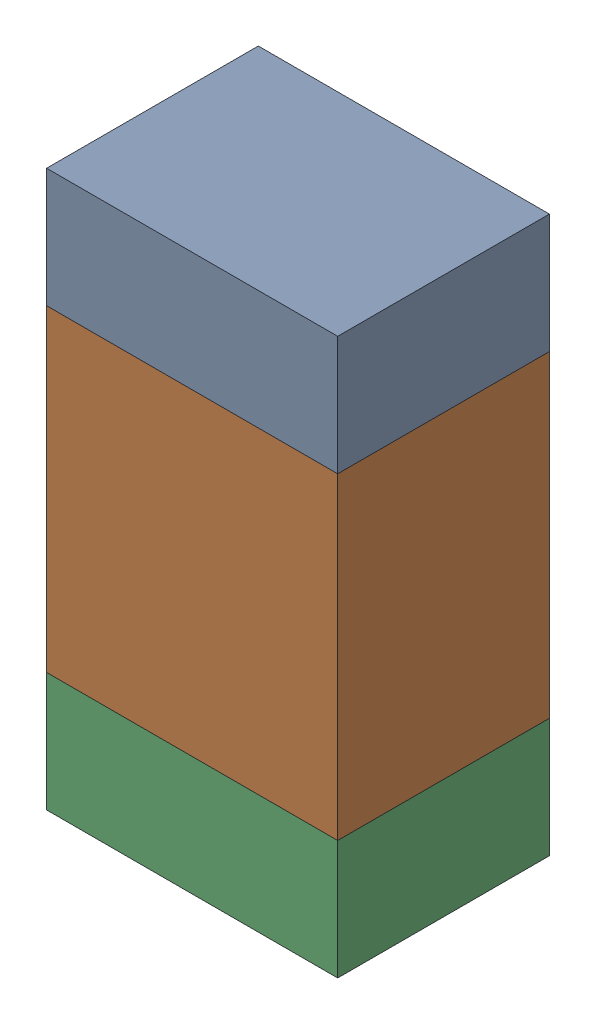
SolidWorks assembly R600_3PCB, configuration Default. Lengths in mm.
Overall size (0.55 1.05 0.4).
6 component instances, 2 part files, 0 mates.
Components (placement in the parent):
- 846483288-1: 846483288 [Default] at (105.6284 96.8624 -2.0638) size (0.55 0.22 0.4)
  - Extruded_12-1: Extruded_12 [Default] at origin size (0.55 0.22 0.4)
- 846483424-1: 846483424 [Default] at (105.6284 96.4499 -2.0638) size (0.55 0.6 0.4)
  - Extruded_13-1: Extruded_13 [Default] at origin size (0.55 0.6 0.4)
- 846483288-2: 846483288 [Default] at (105.6284 96.0374 -2.0638) size (0.55 0.22 0.4)
  - Extruded_12-1: Extruded_12 [Default] at origin size (0.55 0.22 0.4)
